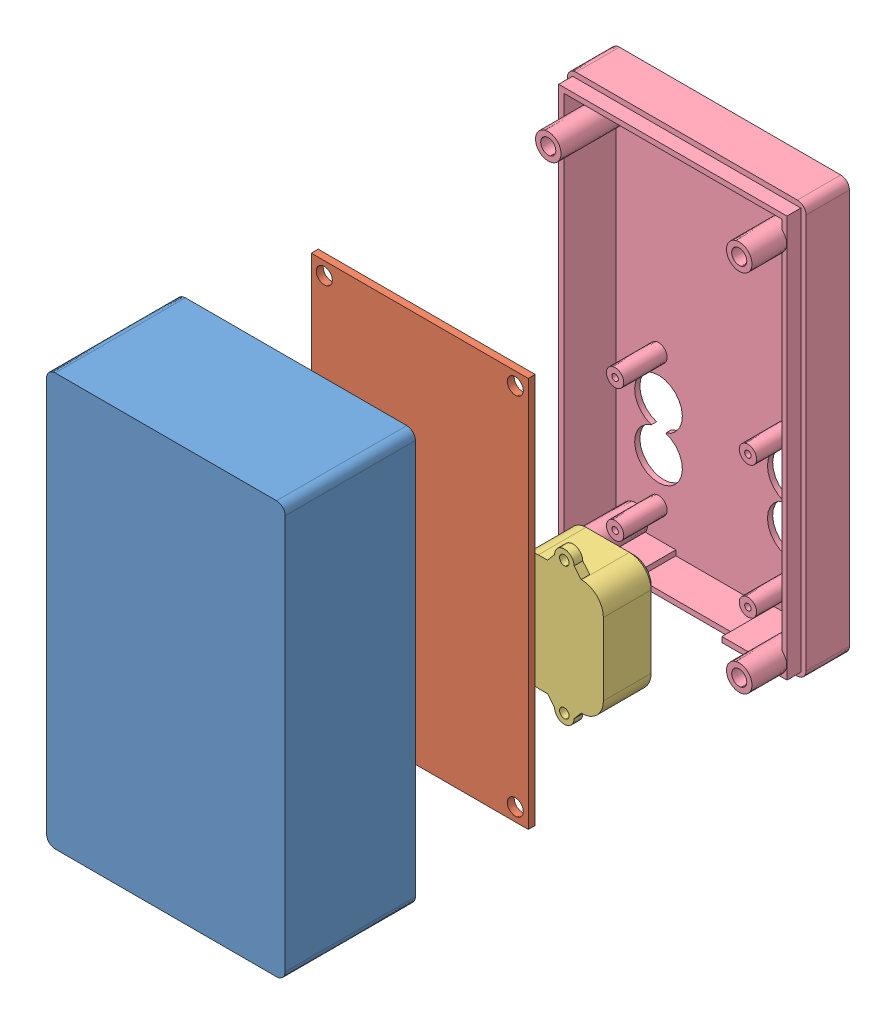
SolidWorks assembly CompleteAssembly, configuration Default. Lengths in mm.
Overall size (55 95 130).
5 component instances, 4 part files, 11 mates.
Components (placement in the parent):
- Case-2: Case [Default] at (91.012 126.0881 46.3299) x (-1 0 0) z (0 0 1) size (55 95 30)
- pcb_main-3: pcb_main [Default] at (39.812 127.2856 19.1299) x (1 0 0) z (0 1 0) size (50 4.6 90)
- Sensor LUNA-1: Sensor LUNA [Valor predeterminado] at (78.312 150.6131 -0.1701) x (0 1 0) z (-1 0 0) size (35 13.5 21.15)
- Sensor LUNA-2: Sensor LUNA [Valor predeterminado] at (48.712 150.6131 -0.1701) x (0 -1 0) z (1 0 0) size (35 13.5 21.15)
- Lid-1: Lid [Default] at (36.012 126.0881 -53.6701) x (1 0 0) z (0 1 0) size (55 21.2 95)
Mates (geometry in assembly coordinates):
- Distance2: distance = 40 mm anti-aligned: plane of pcb_main-3 through (39.812 127.2856 19.1299) normal (0 0 1); plane of Case-2 through (86.812 130.2881 59.1299) normal (0 0 -1)
- Concentric5: concentric anti-aligned: circle of Case-2; circle of pcb_main-3
- Distance4: distance = 90 mm anti-aligned: plane of Lid-1 through (36.012 126.0881 -43.6701) normal (0 0 1); plane of Case-2 through (91.012 126.0881 46.3299) normal (0 0 -1)
- Coincident18: coincident aligned: plane of Sensor LUNA-2 through (48.212 150.6131 -13.6701) normal (0 0 -1); plane of Sensor LUNA-1 through (78.812 150.6131 -13.6701) normal (0 0 -1)
- Coincident19: coincident aligned: plane of Case-2 through (91.012 221.0881 76.3299) normal (0 1 0); plane of Lid-1 through (36.012 221.0881 -43.6701) normal (0 1 0)
- Coincident20: coincident aligned: plane of Case-2 through (36.012 126.0881 76.3299) normal (-1 0 0); plane of Lid-1 through (36.012 126.0881 -43.6701) normal (-1 0 0)
- Concentric15: concentric anti-aligned: circle of Sensor LUNA-1; circle of Lid-1
- Concentric16: concentric anti-aligned: circle of Sensor LUNA-1; circle of Lid-1
- Concentric17: concentric anti-aligned: circle of Sensor LUNA-2; circle of Lid-1
- Concentric19: concentric anti-aligned: circle of Sensor LUNA-2; circle of Lid-1
- Distance6: distance = 40 mm aligned: plane of Sensor LUNA-1 through (78.812 150.6131 -13.6701) normal (0 0 -1); plane of Lid-1 through (36.012 126.0881 -53.6701) normal (0 0 -1)
